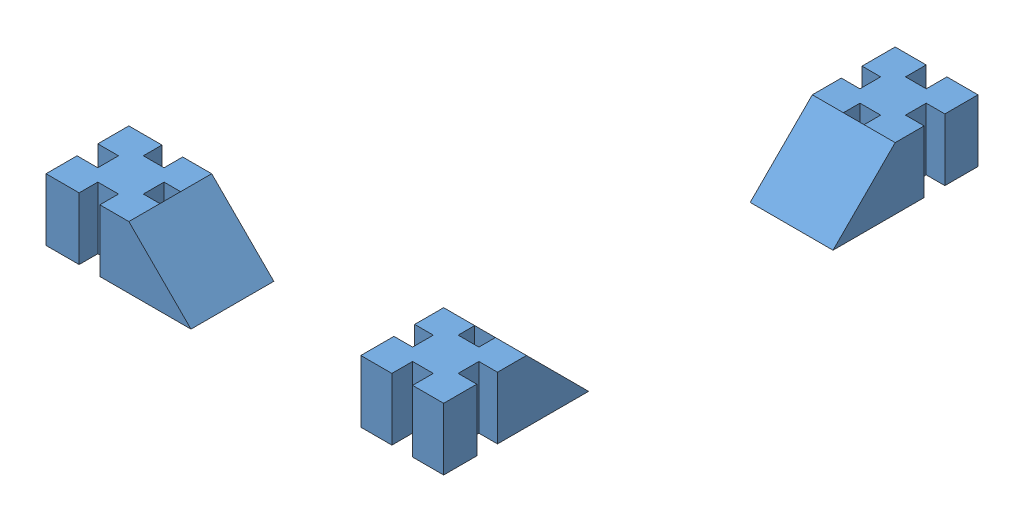
SolidWorks assembly JPAB 2003 6150, configuration Default. Lengths in mm.
Overall size (96 15 129).
3 component instances, 1 part files, 0 mates.
Components (placement in the parent):
- square-1: square [Default] at (38 -8.4985 54.5) x (-1 0 0) z (0 0 1) size (20 15 35)
- square-2: square [Default] at (38 -8.4985 -54.5) x (1 0 0) z (0 0 -1) size (20 15 35)
- square-5: square [Default] at (-38 -8.4985 54.5) x (0 0 -1) z (-1 0 0) size (20 15 35)
